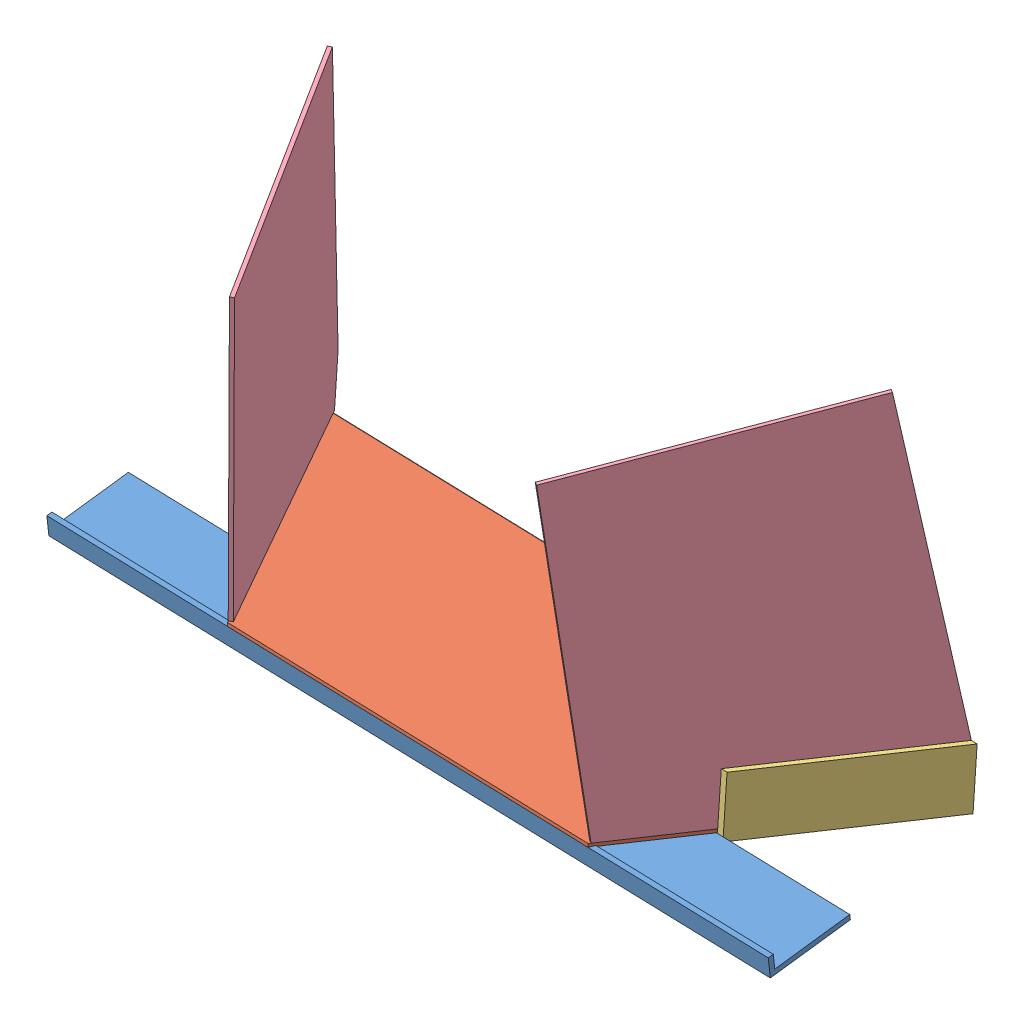
SolidWorks assembly Intake, configuration Default. Lengths in mm.
Overall size (457.63 253.45 202.37).
6 component instances, 5 part files, 11 mates.
Components (placement in the parent):
- Bottom bar-1: Bottom bar [Default] at (407.7679 551.5184 1052.8841) x (0.999568 -0.029337 0.001473) z (-0.005419 -0.13488 0.990847) size (457.2 12.13 50.8)
- Bottom Plate-1: Bottom Plate [Default] at (838.8698 544.9266 902.8734) x (-0.999568 0.029337 -0.001473) z (0.000324 -0.039153 -0.999233) size (404.58 2.06 152.4)
- Wall Angle-1: Wall Angle [Default] at (773.4712 548.3476 1022.2538) x (-0.86549 0.00583 -0.500892) z (0.500065 -0.048576 -0.864625) size (38.1 38.1 137.92)
- Side wall-1: Side wall [Default] at (836.8857 546.9953 901.6097) x (0.029372 0.998802 -0.039126) z (0.86549 -0.00583 0.500892) size (228.94 209.91 2.36)
- Wall Angle B-2: Wall Angle B [Default] at (430.7101 553.7321 902.3962) x (0.865814 -0.044983 -0.498341) z (0.499504 0.019239 0.866098) size (38.1 38.1 138.43)
- Side wall-2: Side wall [Default] at (434.5284 558.8507 902.1968) x (0.029372 0.998802 -0.039126) z (0.865814 -0.044983 -0.498341) size (228.94 209.91 2.36)
Mates (geometry in assembly coordinates):
- Coincident1: coincident: line of Bottom bar-1 through (865.1209 550.1216 1055.1953) axis (-0.999568 0.029337 -0.001473); line of Bottom Plate-1 through (522.3689 560.1813 1054.6901) axis (0.999568 -0.029337 0.001473)
- Width1: width aligned: plane of Bottom Plate-1 through (522.4293 562.2362 1054.6096) normal (-0.865814 0.044983 0.498341); plane of Bottom bar-1 through (750.9307 555.5298 1054.9464) normal (0.86549 -0.00583 0.500892); plane of Bottom Plate-1 through (864.7706 538.1054 1053.5577) normal (0.999568 -0.029337 0.001473); plane of Bottom bar-1 through (407.7679 551.5184 1052.8841) normal (-0.999568 0.029337 -0.001473)
- Coincident3: coincident: line of Bottom bar-1 through (865.1376 548.102 1003.6512) axis (-0.999568 0.029337 -0.001473); plane of Bottom Plate-1 through (838.8698 544.9266 902.8734) normal (-0.029372 -0.998802 0.039126)
- Coincident4: coincident aligned: line of Bottom Plate-1 through (434.468 556.7957 902.2773) axis (0.499504 0.019239 0.866098); line of Wall Angle B-2 through (434.468 556.7957 902.2773) axis (0.499504 0.019239 0.866098)
- Coincident6: coincident anti-aligned: line of Wall Angle B-2 through (434.468 556.7957 902.2773) axis (0.029372 0.998802 -0.039126); line of Bottom Plate-1 through (434.4982 557.8232 902.2371) axis (-0.029372 -0.998802 0.039126)
- Coincident7: coincident aligned: line of Bottom Plate-1 through (750.8702 553.4748 1055.0269) axis (0.500065 -0.048576 -0.864625); line of Wall Angle-1 through (780.8998 550.5578 1003.105) axis (0.500065 -0.048576 -0.864625)
- Coincident16: coincident aligned: line of Bottom Plate-1 through (838.8698 544.9266 902.8734) axis (-0.999568 0.029337 -0.001473); line of Wall Angle-1 through (838.8698 544.9266 902.8734) axis (-0.999568 0.029337 -0.001473)
- Coincident17: coincident aligned: line of Bottom Plate-1 through (750.9307 555.5298 1054.9464) axis (0.500065 -0.048576 -0.864625); line of Side wall-1 through (751.6064 555.4641 1053.778) axis (0.500065 -0.048576 -0.864625)
- Coincident26: coincident anti-aligned: line of Side wall-2 through (521.7543 562.2102 1053.4392) axis (-0.499504 -0.019239 -0.866098); line of Bottom Plate-1 through (435.1217 558.8735 903.2256) axis (0.499504 0.019239 0.866098)
- Coincident27: coincident aligned: line of Wall Angle B-2 through (434.468 556.7957 902.2773) axis (0.029372 0.998802 -0.039126); line of Side wall-2 through (434.5284 558.8507 902.1968) axis (0.029372 0.998802 -0.039126)
- Coincident28: coincident anti-aligned: line of Wall Angle-1 through (839.8956 579.8098 901.5069) axis (-0.029372 -0.998802 0.039126); line of Side wall-1 through (838.9302 546.9816 902.7929) axis (0.029372 0.998802 -0.039126)
